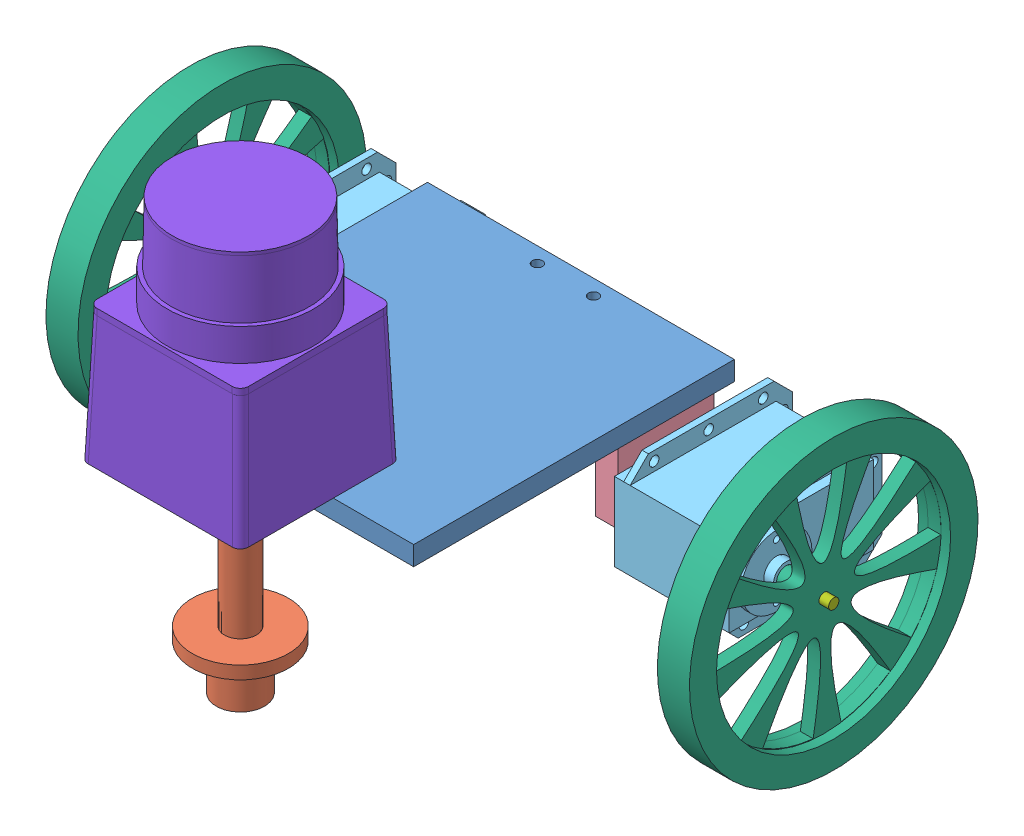
SolidWorks assembly Differential, configuration Default. Lengths in mm.
Overall size (200.68 166.61 174.1).
11 component instances, 8 part files, 29 mates.
Components (placement in the parent):
- base plate-1: base plate [Default] at origin size (95.7 6 100)
- castor-1: castor [Default] at (0.7825 -41 56.9721) x (-0.997467 0 0.071136) z (-0.071136 0 -0.997467) size (30 63 30)
- castorwheel-1: castorwheel [Default] at (0.7825 -54 56.9721) x (-0.599803 0 0.800148) z (0 1 0) size (13 13 17.5)
- motor clamp-2: motor clamp [Default] x (-1 0 0) z (0 0 1) size (84.11 28 30)
- MX-28-1: MX-28 [Default] at (227.8585 63.0507 -670.7152) x (-1 0 0) z (0 0 1) size (43.48 35.8 50.6)
- MX-28-2: MX-28 [Default] at (-228.8539 -116.0004 -670.7152) size (43.48 35.8 50.6)
- wheel-1: wheel [Default] at (-95.84 -26.5401 -29.05) x (0 0.563927 -0.825825) z (0 0.825825 0.563927) size (90 14.8 90)
- shaft-1: shaft [Default] at (-93.44 -26.4668 -29) x (0 -1 0) z (0 0 1) size (3.2 16.6 3.2)
- wheel-2: wheel [Default] at (94.8445 -26.553 -28.9457) x (0 0.611752 0.79105) z (0 0.79105 -0.611752) size (90 14.8 90)
- shaft-2: shaft [Default] at (92.4445 -26.4828 -29) x (0 1 0) z (0 0 1) size (3.2 16.6 3.2)
- laser-1: laser [Default] at (0.7825 6 56.9721) size (50 71 50)
Mates (geometry in assembly coordinates):
- Coincident3: coincident: plane of base plate-1 through (0 0 0) normal (0 0 1); plane of assembly through (0 0 0) normal (0 0 1)
- Coincident4: coincident: plane of base plate-1 through (0 0 0) normal (0 1 0); plane of assembly through (0 0 0) normal (0 1 0)
- Coincident6: coincident aligned: plane of base plate-1 through (0 0 0) normal (1 0 0); plane of assembly through (0 0 0) normal (1 0 0)
- Coincident7: coincident anti-aligned: plane of base plate-1 through (0 3 0) normal (0 1 0); plane of base plate-1 through (47.85 3 -64) normal (0 -1 0)
- Coincident8: coincident aligned: axis of base plate-1 through (8.75 3 -45.1814) axis (0 -1 0); axis of base plate-1 through (8.75 8 -45.1814) axis (0 -1 0)
- Coincident9: coincident anti-aligned: axis of base plate-1 through (0 3 46) axis (0 -1 0); axis of castor-1 through (0 3 46) axis (0 1 0)
- Coincident10: coincident anti-aligned: plane of base plate-1 through (0 3 0) normal (0 1 0); plane of castor-1 through (0.7825 3 56.9721) normal (0 -1 0)
- Lock1: lock: unknown of base plate-1; unknown of castor-1
- Coincident12: coincident anti-aligned: plane of castor-1 through (0.7825 -43 56.9721) normal (0 -1 0); plane of castorwheel-1 through (0.7825 -43 56.9721) normal (0 1 0)
- Coincident13: coincident anti-aligned: axis of castor-1 through (0.7825 -57 56.9721) axis (0 1 0); axis of castorwheel-1 through (0.7825 -43 56.9721) axis (0 -1 0)
- Coincident14: coincident anti-aligned: plane of base plate-1 through (0 -3 0) normal (0 -1 0); plane of motor clamp-2 through (-47.85 -3 -64) normal (0 1 0)
- Coincident15: coincident anti-aligned: axis of base plate-1 through (-8.75 3 -45.1814) axis (0 -1 0); axis of motor clamp-2 through (-8.75 -8 -45.1814) axis (0 1 0)
- Coincident16: coincident anti-aligned: axis of base plate-1 through (8.75 3 -45.1814) axis (0 -1 0); axis of motor clamp-2 through (8.75 -8 -45.1814) axis (0 1 0)
- Coincident17: coincident anti-aligned: axis of motor clamp-2 through (34.5596 -26.4748 -29) axis (1 0 0); axis of MX-28-1 through (45.3445 -26.4748 -29) axis (-1 0 0)
- Parallel1: parallel aligned: plane of base plate-1 through (0 3 0) normal (0 1 0); plane of MX-28-1 through (43.4445 -14.2828 -62) normal (0 1 0)
- Coincident20: coincident aligned: axis of motor clamp-2 through (-42.555 -26.4748 -29) axis (1 0 0); axis of MX-28-2 through (-46.34 -26.4748 -29) axis (1 0 0)
- Coincident22: coincident anti-aligned: plane of motor clamp-2 through (41.5596 -8 0) normal (1 0 0); plane of MX-28-1 through (41.5596 -26.4748 -29) normal (-1 0 0)
- Coincident23: coincident anti-aligned: plane of motor clamp-2 through (-42.555 -8 0) normal (-1 0 0); plane of MX-28-2 through (-42.555 -26.4748 -29) normal (1 0 0)
- Parallel2: parallel aligned: plane of base plate-1 through (0 3 0) normal (0 1 0); plane of MX-28-2 through (-44.44 -14.2668 -17) normal (0 1 0)
- Coincident25: coincident aligned: axis of MX-28-2 through (-86.04 -26.4668 -29) axis (1 0 0); axis of wheel-1 through (-100.84 -26.4668 -29) axis (1 0 0)
- Coincident26: coincident anti-aligned: axis of wheel-1 through (-97.84 -26.4668 -29) axis (1 0 0); axis of shaft-1 through (-86.04 -26.4668 -29) axis (-1 0 0)
- Coincident27: coincident anti-aligned: plane of MX-28-2 through (-84.24 -26.4668 -29) normal (-1 0 0); plane of shaft-1 through (-84.24 -26.4668 -29) normal (1 0 0)
- Coincident28: coincident aligned: plane of wheel-1 through (-100.84 -26.4668 -29) normal (-1 0 0); plane of shaft-1 through (-100.84 -26.4668 -29) normal (-1 0 0)
- Coincident29: coincident aligned: axis of MX-28-1 through (82.0445 -26.4828 -29) axis (-1 0 0); axis of wheel-2 through (99.8445 -26.4828 -29) axis (-1 0 0)
- Coincident30: coincident anti-aligned: axis of wheel-2 through (99.8445 -26.4828 -29) axis (-1 0 0); axis of shaft-2 through (85.0445 -26.4828 -29) axis (1 0 0)
- Coincident31: coincident aligned: plane of wheel-2 through (99.8445 -26.4828 -29) normal (1 0 0); plane of shaft-2 through (99.8445 -26.4828 -29) normal (1 0 0)
- Coincident32: coincident anti-aligned: plane of MX-28-1 through (83.2445 -26.4828 -29) normal (1 0 0); plane of shaft-2 through (83.2445 -26.4828 -29) normal (-1 0 0)
- Coincident33: coincident anti-aligned: plane of castor-1 through (0.7825 6 56.9721) normal (0 1 0); plane of laser-1 through (-24.2175 6 31.9721) normal (0 -1 0)
- Coincident34: coincident anti-aligned: axis of castor-1 through (0.7825 3 56.9721) axis (0 -1 0); axis of laser-1 through (0.7825 58 56.9721) axis (0 1 0)
